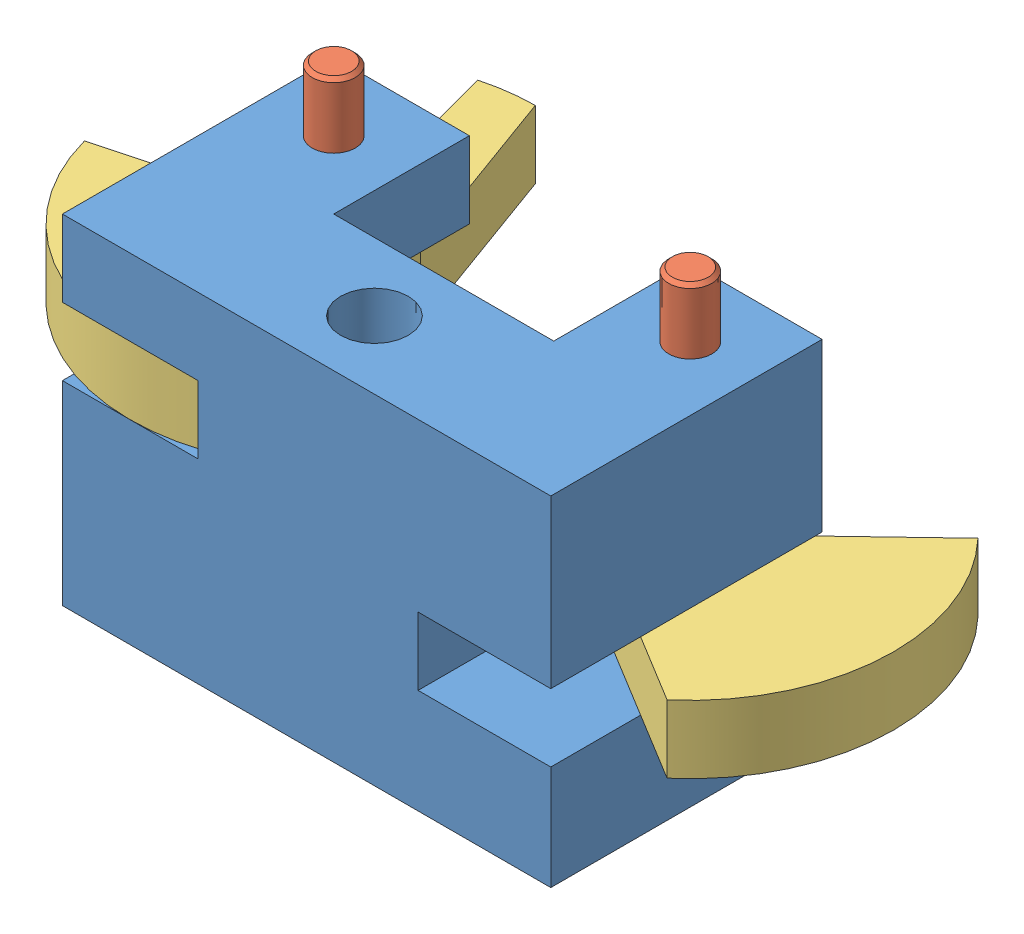
SolidWorks assembly Mockup Stage Assembly, configuration Default. Lengths in mm.
Overall size (174.66 89.3 105.24).
5 component instances, 3 part files, 9 mates.
Components (placement in the parent):
- M-S-002-Stage Mockup-1: M-S-002-Stage Mockup [Default] at origin size (108 75 60)
- M-DPE-006-1: M-DPE-006 [Shorty] at (-39 48.7 -15) x (0.999833 0 0.018288) z (0 -1 0) size (9.53 9.53 56.2)
- M-S-002-Actuator 2-1: M-S-002-Actuator 2 [Default] at (-39 2.5 -15) x (0.5 0 -0.866025) z (0.866025 0 0.5) size (83.76 15 65.39)
- M-S-002-Actuator 2-2: M-S-002-Actuator 2 [Default] at (39.8532 -2.5 -15) x (-0.999712 0 -0.024) z (-0.024 0 0.999712) size (83.76 15 65.39)
- M-DPE-006-2: M-DPE-006 [4" Long] at (39.8532 48.7 -15) x (0.930658 0 -0.36589) z (0 -1 0) size (9.53 9.53 76.2)
Mates (geometry in assembly coordinates):
- Concentric1: concentric aligned: cylinder of M-DPE-006-1 through (-39 -7.5 -15) axis (0 1 0) radius 4.7625; cylinder of M-S-002-Stage Mockup-1 through (-39 -30.9704 -15) axis (0 1 0) radius 4.7625
- Coincident1: coincident anti-aligned: plane of M-S-002-Stage Mockup-1 through (-54 -7.5 30) normal (0 1 0); plane of M-DPE-006-1 through (-39 -7.5 -15) normal (0 -1 0)
- Concentric2: concentric anti-aligned: cylinder of M-DPE-006-1 through (-39 -7.5 -15) axis (0 1 0) radius 4.7625; cylinder of M-S-002-Actuator 2-1 through (-39 17.5 -15) axis (0 -1 0) radius 4.7625
- Coincident2: coincident anti-aligned: plane of M-S-002-Stage Mockup-1 through (-24 17.5 30) normal (0 -1 0); plane of M-S-002-Actuator 2-1 through (-39 17.5 -15) normal (0 1 0)
- Concentric3: concentric aligned: cylinder of M-S-002-Stage Mockup-1 through (39.8532 -50.9704 -15) axis (0 1 0) radius 4.7625; cylinder of M-DPE-006-2 through (39.8532 -27.5 -15) axis (0 1 0) radius 4.7625
- Coincident3: coincident anti-aligned: plane of M-S-002-Stage Mockup-1 through (24.6547 -27.5 30) normal (0 1 0); plane of M-DPE-006-2 through (39.8532 -27.5 -15) normal (0 -1 0)
- Concentric4: concentric aligned: cylinder of M-S-002-Actuator 2-2 through (39.8532 -17.5 -15) axis (0 1 0) radius 4.7625; cylinder of M-DPE-006-2 through (39.8532 -27.5 -15) axis (0 1 0) radius 4.7625
- Coincident4: coincident anti-aligned: plane of M-S-002-Stage Mockup-1 through (54 -2.5 30) normal (0 -1 0); plane of M-S-002-Actuator 2-2 through (39.8532 -2.5 -15) normal (0 1 0)
- LimitAngle1: limit planar angle = 0 rad anti-aligned: plane of M-S-002-Stage Mockup-1 through (-24 2.5 30) normal (-1 0 0); plane of M-S-002-Actuator 2-1 through (-24.9046 2.5 -20.1303) normal (1 0 0)
